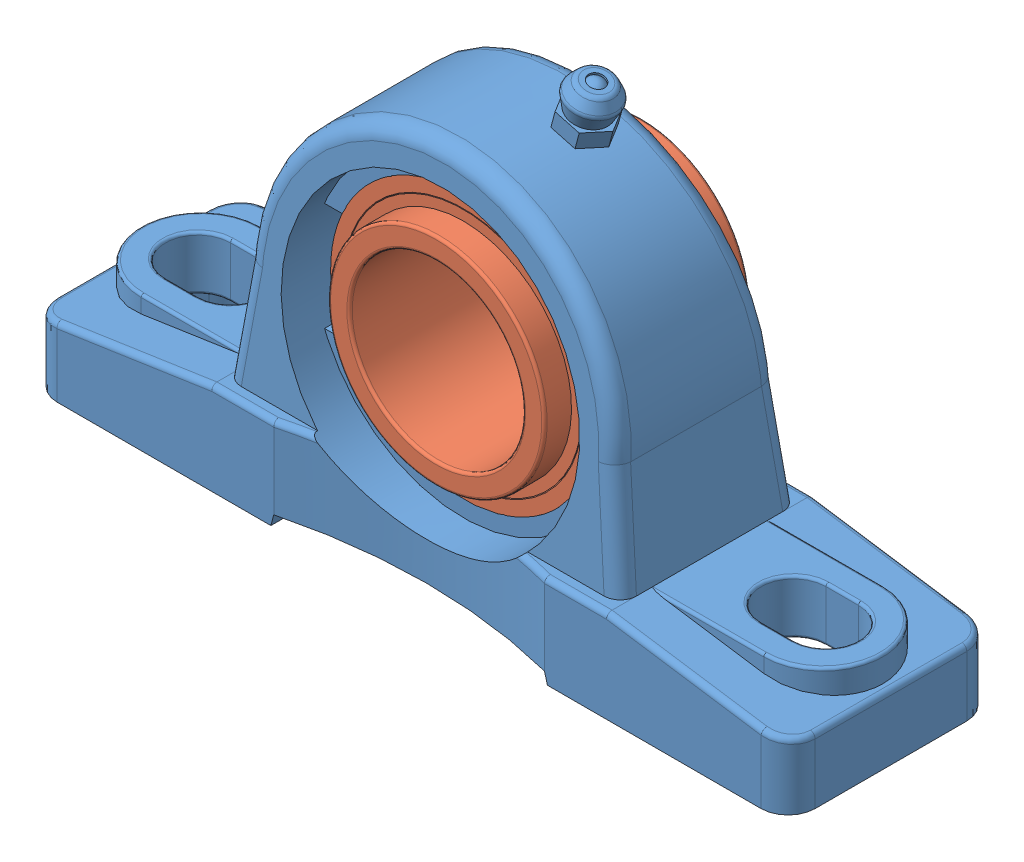
SolidWorks assembly rulman_montaj, configuration Varsayılan. Lengths in mm.
Overall size (140 78.23 43.15).
2 component instances, 2 part files, 2 mates.
Components (placement in the parent):
- rulman_ana_parça-1: rulman_ana_parça [Varsayılan] at (-14.4158 -17.7259 139.9246) size (140 78.23 38.15)
- rulman_iç_kısım-1: rulman_iç_kısım [Varsayılan] at (-14.4181 10.2741 139.9246) x (0 0 1) z (0.973203 -0.229946 0) size (38 50.56 50.56)
Mates (geometry in assembly coordinates):
- Çakışık2: coincident: rulman_ana_parça-1, rulman_iç_kısım-1
- Çakışık3: coincident: rulman_ana_parça-1, rulman_iç_kısım-1
